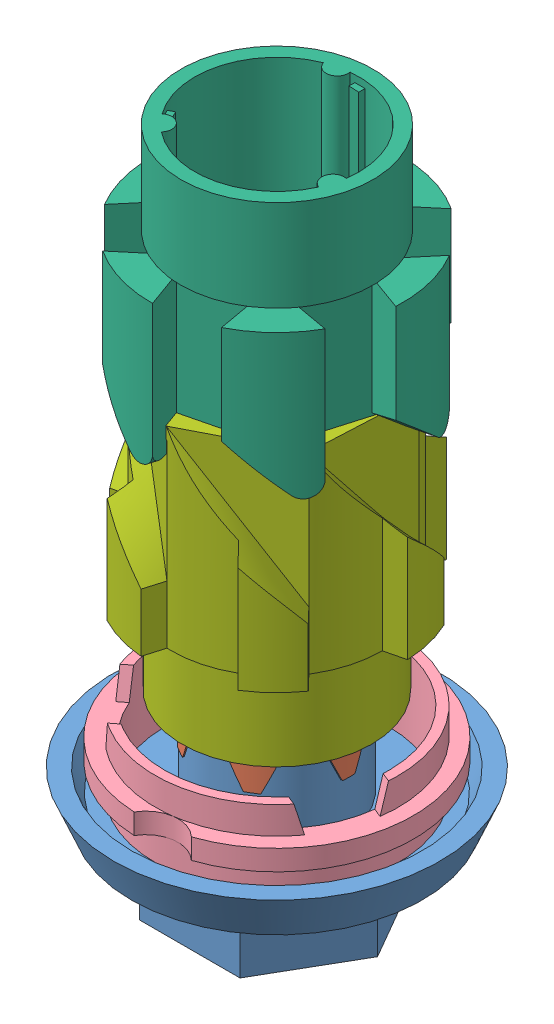
SolidWorks assembly Cylinder_Rotator, configuration Default. Lengths in mm.
Overall size (25.03 47.62 25.04).
7 component instances, 7 part files, 13 mates.
Components (placement in the parent):
- Cylinder_Rotator_pt1-1: Cylinder_Rotator_pt1 [Default] at (18.8958 8.6532 27.1526) size (23.17 32.6 23.17)
- Cylinder_Rotator_pt2-1: Cylinder_Rotator_pt2 [Default] at (18.8958 18.6132 27.1526) x (-0.510192 0 -0.860061) z (0.860061 0 -0.510192) size (10.13 14.17 10.13)
- Cylinder_Rotator_Spring-1: Cylinder_Rotator_Spring [Default] at (19.0112 24.4693 27.2364) size (6.17 17.01 6.17)
- Cylinder_Rotator_Ring-1: Cylinder_Rotator_Ring [Default] at (18.8958 15.2032 27.1526) x (-0.990155 0 0.139974) z (-0.139974 0 -0.990155) size (19.4 5.35 19.23)
- Cylinder_Rotator_Screw-1: Cylinder_Rotator_Screw [Default] at (18.8943 33.5132 27.1524) x (-0.438039 0 0.898956) z (-0.898956 0 -0.438039) size (6.55 9.42 6.55)
- Cylinder_Rotator_pt3-1: Cylinder_Rotator_pt3 [Default] at (18.9009 56.2732 27.1494) x (-0.691686 0 -0.722198) z (-0.722198 0 0.691686) size (17.88 16.85 17.54)
- Cylinder_Rotator_pt4-1: Cylinder_Rotator_pt4 [Default] at (18.8958 21.5032 27.1526) x (0.960127 0 0.279563) z (-0.279563 0 0.960127) size (19.34 22.93 19.73)
Mates (geometry in assembly coordinates):
- Coincident2: coincident anti-aligned: plane of Cylinder_Rotator_pt1-1 through (18.8958 18.6132 27.1526) normal (0 1 0); plane of Cylinder_Rotator_pt2-1 through (18.8958 18.6132 27.1526) normal (0 -1 0)
- Concentric1: concentric anti-aligned: cylinder of Cylinder_Rotator_pt1-1 through (18.8958 41.2532 27.1526) axis (0 -1 0) radius 2.36; cylinder of Cylinder_Rotator_pt2-1 through (18.8958 25.1932 27.1526) axis (0 1 0) radius 4.161
- Lock1: lock: unknown of Cylinder_Rotator_pt2-1; unknown of Cylinder_Rotator_Spring-1
- Lock2: lock: unknown of Cylinder_Rotator_pt1-1; unknown of Cylinder_Rotator_pt2-1
- Concentric3: concentric aligned: cylinder of Cylinder_Rotator_pt1-1 through (18.8958 18.9997 27.1526) axis (0 1 0) radius 4.95; cylinder of Cylinder_Rotator_Ring-1 through (18.8958 15.2032 27.1526) axis (0 1 0) radius 7.99
- Coincident4: coincident anti-aligned: plane of Cylinder_Rotator_pt1-1 through (28.5709 15.2032 27.1526) normal (0 1 0); plane of Cylinder_Rotator_Ring-1 through (18.8958 15.2032 27.1526) normal (0 -1 0)
- Concentric4: concentric aligned: cylinder of Cylinder_Rotator_pt1-1 through (18.8958 41.2532 27.1526) axis (0 -1 0) radius 2.36; cylinder of Cylinder_Rotator_pt4-1 through (18.8958 40.4732 27.1526) axis (0 -1 0) radius 5.3
- Coincident5: coincident aligned: circle of Cylinder_Rotator_pt1-1; circle of Cylinder_Rotator_pt4-1
- Lock3: lock: unknown of Cylinder_Rotator_pt1-1; unknown of Cylinder_Rotator_pt4-1
- Tangent5: tangent: cylinder of Cylinder_Rotator_pt1-1 through (18.8958 12.8868 27.1526) axis (0 1 0) radius 1.3635; curve of Cylinder_Rotator_Screw-1
- Coincident7: coincident anti-aligned: circle of Cylinder_Rotator_pt3-1; circle of Cylinder_Rotator_pt4-1
- Lock4: lock: unknown of Cylinder_Rotator_pt3-1; unknown of Cylinder_Rotator_pt4-1
- Coincident9: coincident anti-aligned: plane of Cylinder_Rotator_pt1-1 through (18.8958 41.2532 27.1526) normal (0 1 0); plane of Cylinder_Rotator_Screw-1 through (18.8943 41.2532 27.1524) normal (0 -1 0)
